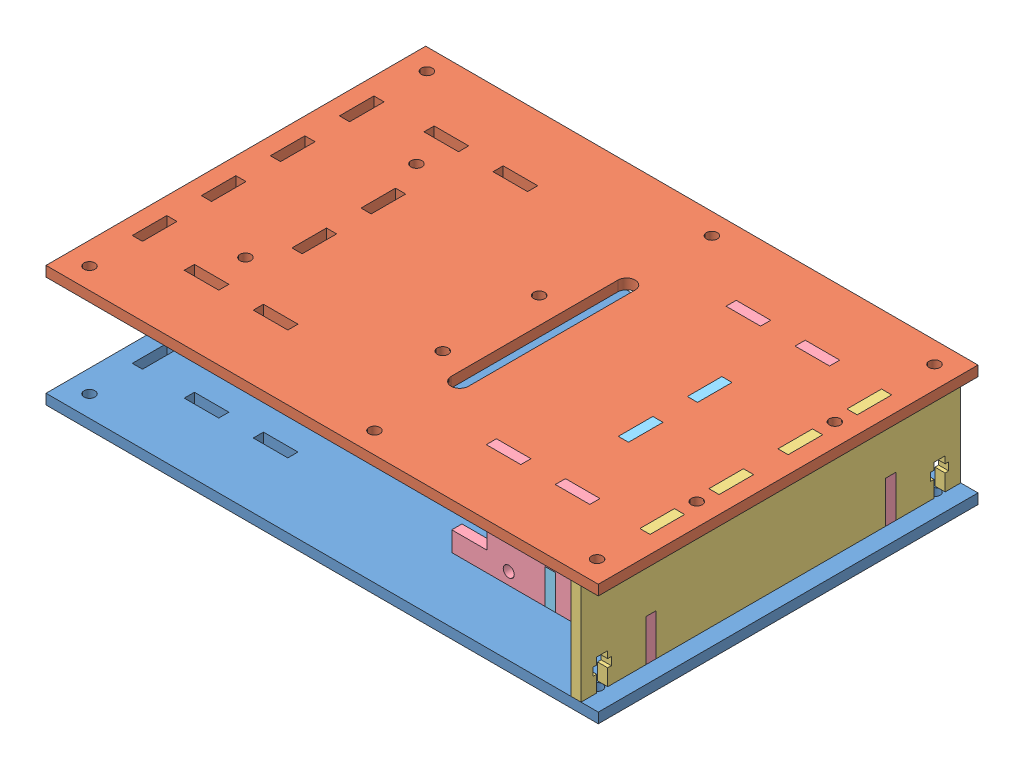
SolidWorks assembly Test Assembly, configuration Default. Lengths in mm.
Overall size (160 35.03 110).
6 component instances, 5 part files, 17 mates.
Components (placement in the parent):
- Bottom Plate-1: Bottom Plate [Default] at (-20.8321 23.9939 -2.5281) size (160 2.95 110)
- Top Plate-1: Top Plate [Default] at (-20.8321 56.0739 -2.5281) size (160 2.95 110)
- Front Plate-1: Front Plate [Default] at (-20.8321 26.9439 -2.5281) x (1 0 0) z (0 1 0) size (2.95 110 35.03)
- Motor Adapter-6: Motor Adapter [Default] at (22.0733 39.0089 -35.7821) x (1 0 0) z (0 1 0) size (56.25 2.95 35.03)
- Motor Adapter-7: Motor Adapter [Default] at (22.0733 39.0089 33.6759) x (1 0 0) z (0 1 0) size (56.25 2.95 35.03)
- Battery Holder-1: Battery Holder [Default] at (27.9179 39.0089 -35.7821) x (0 1 0) z (-1 0 0) size (32.08 72.41 2.95)
Mates (geometry in assembly coordinates):
- Coincident5: coincident aligned: plane of Bottom Plate-1 through (-100.8321 26.9439 52.4719) normal (0 0 1); plane of Top Plate-1 through (-100.8321 59.0239 52.4719) normal (0 0 1)
- Coincident6: coincident aligned: plane of Bottom Plate-1 through (59.1679 26.9439 -57.5281) normal (1 0 0); plane of Top Plate-1 through (59.1679 59.0239 -57.5281) normal (1 0 0)
- InPlace1: in place: plane of Bottom Plate-1 through (-20.8321 26.6939 -2.5281) normal (0 1 0); plane of ? through (0 26.6939 0) normal (0 1 0); moOrthogonalPlaneRef_w of Bottom Plate-1 through (-20.8321 26.6939 -2.5281) normal (0 1 0); plane of ? through (0 26.6939 0) normal (0 0 -1); plane of Bottom Plate-1 through (-20.8321 26.6939 -2.5281) normal (0 1 0); plane of ? through (0 26.6939 0) normal (1 0 0); plane of Bottom Plate-1 through (-20.8321 26.9439 -2.5281) normal (0 1 0); unknown of Front Plate-1
- Coincident7: coincident aligned: plane of Bottom Plate-1; plane of Front Plate-1
- Coincident8: coincident aligned: moOrthogonalPlaneRef_w of Bottom Plate-1 through (-20.8321 26.9439 -2.5281) normal (0 0 -1); plane of Front Plate-1 through (-20.8321 26.9439 -2.5281) normal (0 0 -1)
- Coincident9: coincident anti-aligned: moOrthogonalPlaneRef_w of Bottom Plate-1 through (-20.8321 26.9439 -2.5281) normal (-1 0 0); plane of Front Plate-1 through (-20.8321 26.9439 -2.5281) normal (1 0 0)
- Coincident7: coincident anti-aligned: plane of Bottom Plate-1 through (-20.8321 26.9439 -2.5281) normal (0 1 0); plane of Motor Adapter-6 through (37.9179 26.9439 -35.7821) normal (0 -1 0)
- Coincident8: coincident anti-aligned: plane of Bottom Plate-1 through (37.9179 23.9939 -38.7321) normal (-1 0 0); plane of Motor Adapter-6 through (37.9179 23.9939 -35.7821) normal (1 0 0)
- Coincident9: coincident anti-aligned: plane of Bottom Plate-1 through (37.9179 23.9939 -38.7321) normal (0 0 1); plane of Motor Adapter-6 through (22.0733 39.0089 -38.7321) normal (0 0 -1)
- Coincident10: coincident anti-aligned: plane of Bottom Plate-1 through (-20.8321 26.9439 -2.5281) normal (0 1 0); plane of Motor Adapter-7 through (37.9179 26.9439 33.6759) normal (0 -1 0)
- Coincident11: coincident anti-aligned: plane of Front Plate-1 through (54.1679 39.0089 33.6759) normal (0 0 -1); plane of Motor Adapter-7 through (22.0733 39.0089 33.6759) normal (0 0 1)
- Coincident12: coincident anti-aligned: plane of Front Plate-1 through (51.2179 166.1134 52.4719) normal (-1 0 0); plane of Motor Adapter-7 through (51.2179 166.1134 121.9299) normal (1 0 0)
- InPlace2: in place: plane of ? through (27.9179 23.9939 -36.0321) normal (-1 0 0); plane of ? through (27.9179 0 0) normal (-1 0 0); plane of ? through (27.9179 23.9939 -36.0321) normal (-1 0 0); plane of ? through (27.9179 0 0) normal (0 1 0); plane of ? through (27.9179 23.9939 -36.0321) normal (-1 0 0); plane of ? through (27.9179 0 0) normal (0 0 1); plane of Motor Adapter-6 through (27.9179 23.9939 -35.7821) normal (-1 0 0); unknown of Battery Holder-1
- Coincident13: coincident aligned: plane of Motor Adapter-6; plane of Battery Holder-1
- Coincident14: coincident aligned: moOrthogonalPlaneRef_w of Motor Adapter-6 through (27.9179 39.0089 -35.7821) normal (0 0 -1); plane of Battery Holder-1 through (27.9179 39.0089 -35.7821) normal (0 0 -1)
- Coincident15: coincident anti-aligned: moOrthogonalPlaneRef_w of Motor Adapter-6 through (27.9179 39.0089 -35.7821) normal (0 -1 0); plane of Battery Holder-1 through (27.9179 39.0089 -35.7821) normal (0 1 0)
- Coincident13: coincident anti-aligned: plane of Top Plate-1 through (-20.8321 56.0739 -2.5281) normal (0 -1 0); plane of Motor Adapter-6 through (37.9179 56.0739 -35.7821) normal (0 1 0)
